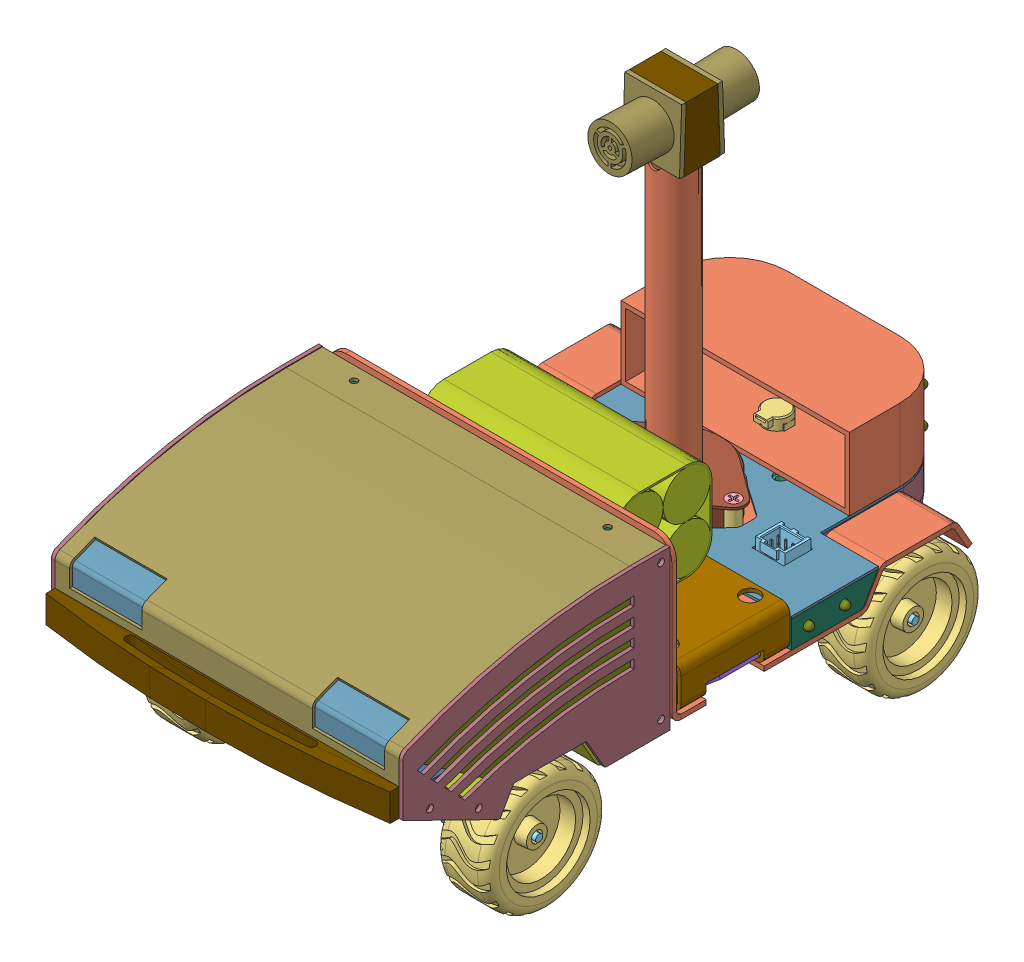
SolidWorks assembly ASSEMBLY, TEST, configuration Default. Lengths in mm.
Overall size (124.43 170.93 223.86).
89 component instances, 42 part files, 3 mates.
Components (placement in the parent):
- SCOUT, TOP LEVEL-1: SCOUT, TOP LEVEL [Default] at (-54.0107 -26.6072 26.8568) size (124.43 170.93 223.86)
  - 6655k13 Thrust Washers-1: 6655k13 Thrust Washers [Default] at (-7.8856 2.7539 2.2902) size (14.15 14.15 4.9)
  - REAR, TOP LEVEL-1: REAR, TOP LEVEL [Default] at (-50.0168 -33.3245 -47.0081) x (-1 0 0) z (0 0 -1) size (124.43 170.93 120.66)
    - PLATE, REAR-1: PLATE, REAR [Default] at (-42.1312 28.0774 12.7174) size (120.65 55.63 120.66)
    - WHEEL ASSEMBLY-1: WHEEL ASSEMBLY [Default] at (7.6153 26.9792 58.7651) x (0 0 1) z (1 0 0) size (42.46 78.6 70.03) (flexible)
      - Pololu 49x19 Wheel-1: Pololu 49x19 Wheel [Default] at (-19.8703 11.8393 2.4418) size (42.46 42.56 19)
      - Pololu Extended Micro Metal Bracket-1: Pololu Extended Micro Metal Bracket [Default] at (-19.8703 6.8393 -18.4366) size (26.6 22.49 26.04)
      - Pololu 298-1 Motor-1: Pololu 298-1 Motor [Default] at (-19.8703 11.8393 -25.1366) x (0 0 -1) z (0 1 0) size (35.87 12 10)
    - WHEEL ASSEMBLY-2: WHEEL ASSEMBLY [Default] at (-91.8778 26.9792 19.0244) x (0 0 -1) z (-1 0 0) size (42.46 78.6 70.03) (flexible)
      - Pololu 49x19 Wheel-1: Pololu 49x19 Wheel [Default] at (-19.8703 11.8393 2.4418) size (42.46 42.56 19)
      - Pololu Extended Micro Metal Bracket-1: Pololu Extended Micro Metal Bracket [Default] at (-19.8703 6.8393 -18.4366) size (26.6 22.49 26.04)
      - Pololu 298-1 Motor-1: Pololu 298-1 Motor [Default] at (-19.8703 11.8393 -25.1366) x (0 0 -1) z (0 1 0) size (35.87 12 10)
    - Socket Head Cap Screw_AI-9: Socket Head Cap Screw_AI [HX-SHCS 0.086-56x0.4375x0.4375-N] at (-77.6912 31.9128 47.8948) x (0 -1 0) z (-0.381305 0 -0.924449) size (13.3 3.56 3.56)
    - Socket Head Cap Screw_AI-10: Socket Head Cap Screw_AI [HX-SHCS 0.086-56x0.4375x0.4375-N] at (-77.6912 31.9128 29.8948) x (0 -1 0) z (0 0 1) size (13.3 3.56 3.56)
    - Socket Head Cap Screw_AI-11: Socket Head Cap Screw_AI [HX-SHCS 0.086-56x0.4375x0.4375-N] at (-6.5712 31.9128 29.8948) x (0 -1 0) z (0 0 1) size (13.3 3.56 3.56)
    - Socket Head Cap Screw_AI-12: Socket Head Cap Screw_AI [HX-SHCS 0.086-56x0.4375x0.4375-N] at (-6.5712 31.9128 47.8948) x (0 -1 0) z (0 0 1) size (13.3 3.56 3.56)
    - 4000mAh 7.4V Battery Pack-1: 4000mAh 7.4V Battery Pack [Default] at (-42.1312 61.2244 -25.3842) x (0 0 -1) z (1 0 0) size (34.29 34.29 68.58)
    - SENSOR, GP2Y0D810-1: SENSOR, GP2Y0D810 [Default] at (9.9271 36.6454 -23.9419) x (0 0 -1) z (0.766044 0.642788 0) size (28.32 10.54 8.89)
    - SENSOR, GP2Y0D810-2: SENSOR, GP2Y0D810 [Default] at (-94.1896 36.6454 -23.9419) x (0 0 -1) z (0.766044 -0.642788 0) size (28.32 10.54 8.89)
    - Battery Support-1: Battery Support [Default] at (-42.1312 29.7284 -26.0192) size (120.65 27.05 38.1)
    - Mounting Block-1: Mounting Block [Default] at (-42.1312 36.0784 -35.6712) x (-1 0 0) z (0 0 -1) size (25.4 12.7 25.4)
    - PF35T-48-1: PF35T-48 [Default] at (-42.1312 31.7284 12.5888) x (-1 0 0) z (0 0 -1) size (50 29.2 35)
    - MaxSonar EZ1-1: MaxSonar EZ1 [Default] at (-42.1312 153.1691 6.6293) x (-1 0 0) z (0 0.034899 -0.999391) size (19.94 22.1 16.38)
    - MaxSonar EZ1-2: MaxSonar EZ1 [Default] at (-42.1312 153.1691 18.5483) x (1 0 0) z (0 0.034899 0.999391) size (19.94 22.1 16.38)
    - BUMPER, REAR-1: BUMPER, REAR [Default] at (-42.1312 29.7284 53.2288) x (-1 0 0) z (0 0 -1) size (80.01 9.53 54.3)
    - PLATE, REAR COVER-1: PLATE, REAR COVER [Default] at (-42.1312 39.2534 72.2788) size (120.65 0.81 81.14)
    - MOUNTING BLOCK, COLOR SENSOR-1: MOUNTING BLOCK, COLOR SENSOR [Default] at (-97.6937 29.7284 5.6038) size (9.53 9.53 30.46)
    - MOUNTING BLOCK, COLOR SENSOR-2: MOUNTING BLOCK, COLOR SENSOR [Default] at (13.4313 29.7284 5.6038) size (9.53 9.53 30.46)
    - SENSOR, COLOR LED-1: SENSOR, COLOR LED [Default] at (-24.0807 23.782 31.9371) x (0 0 -1) z (-0.409692 -0.912224 0) size (5.83 3.66 3.66)
    - SENSOR, COLOR LED-2: SENSOR, COLOR LED [Default] at (-67.3741 22.996 31.9371) x (0 0 -1) z (-0.202984 -0.979182 0) size (5.83 3.66 3.66)
    - COPPER CONTACT-1: COPPER CONTACT [Default] at (-53.2437 34.4909 64.0238) size (15.88 6.35 4.45)
    - COPPER CONTACT-2: COPPER CONTACT [Default] at (-31.0187 34.4909 64.0238) size (15.88 6.35 4.45)
    - MOUNTING BLOCK, SONAR-1: MOUNTING BLOCK, SONAR [Default] at (-42.1312 153.0989 12.5888) x (-1 0 0) z (0 0 -1) size (19.94 22.23 12.7)
    - SHAFT, SONAR MOUNT-1: SHAFT, SONAR MOUNT [Default] at (-42.1312 52.5784 12.5888) x (-0.538443 0 0.842662) z (-0.842662 0 -0.538443) size (4.76 102.11 4.76)
    - SHAFT, SONAR SUPPORT-1: SHAFT, SONAR SUPPORT [Default] at (-42.1312 46.7284 12.5888) x (0.999987 0 0.005105) z (-0.005105 0 0.999987) size (14.22 95.57 14.22)
    - SHAFT, STEPPER SUPPORT-1: SHAFT, STEPPER SUPPORT [Default] at (-63.1312 29.6724 12.5888) size (4.76 16.26 4.76)
    - SHAFT, STEPPER SUPPORT-2: SHAFT, STEPPER SUPPORT [Default] at (-21.1312 29.6724 12.5888) x (0.987866 0 -0.155311) z (0.155311 0 0.987866) size (4.76 16.26 4.76)
    - Flat Head 100 Screw_AI-6: Flat Head 100 Screw_AI [CR-FHM1 0.112-40x0.25x0.25-N] at (-63.1312 46.7284 12.5888) x (0 -1 0) z (0 0 1) size (6.35 4.85 4.85)
    - Flat Head 100 Screw_AI-7: Flat Head 100 Screw_AI [CR-FHM1 0.112-40x0.25x0.25-N] at (-21.1312 46.7284 12.5888) x (0 -1 0) z (0 0 1) size (6.35 4.85 4.85)
    - CONNECTOR, MOLEX 6 PIN-1: CONNECTOR, MOLEX 6 PIN [Default] at (-80.2263 37.7912 12.5433) size (10.34 13.8 9.75)
    - SENSOR, COLOR LED-3: SENSOR, COLOR LED [Default] at (-64.0196 42.7147 3.5765) x (1 0 0) z (0 0.700538 -0.713616) size (5.83 3.66 3.66)
    - SENSOR, COLOR LED-4: SENSOR, COLOR LED [Default] at (-64.0196 42.7147 -9.1235) x (1 0 0) z (0 0.700538 -0.713616) size (5.83 3.66 3.66)
    - SENSOR, COLOR LED-5: SENSOR, COLOR LED [Default] at (-20.2429 42.7147 20.3311) x (-1 0 0) z (0 0.700538 0.713616) size (5.83 3.66 3.66)
    - SENSOR, COLOR LED-6: SENSOR, COLOR LED [Default] at (-20.2429 42.7147 7.6311) x (-1 0 0) z (0 0.700538 0.713616) size (5.83 3.66 3.66)
    - MOUNTING BLOCK, REAR-1: MOUNTING BLOCK, REAR [Default] at (-58.0062 34.4909 31.0038) size (9.53 9.53 28.57)
    - MOUNTING BLOCK, REAR-2: MOUNTING BLOCK, REAR [Default] at (-26.2562 34.4909 31.0038) size (9.53 9.53 28.57)
    - SW3dPS-Sliderswitch-1: SW3dPS-Sliderswitch [Standard] at (-81.1109 44.0794 -21.7288) (suppressed, hidden)
  - FRONT, TOP LEVEL-1: FRONT, TOP LEVEL [Default] at (-84.349 -51.7544 28.3431) x (-1 0 0) z (0 0 -1) size (123.38 89.85 131.19)
    - PLATE, FRONT-1: PLATE, FRONT [Default] at (-76.4634 46.5072 -32.0242) size (120.65 12.1 60.8)
    - WHEEL ASSEMBLY-1: WHEEL ASSEMBLY [Default] at (-26.7168 45.4091 2.1802) x (0 0 1) z (1 0 0) size (42.46 78.6 70.03) (flexible)
      - Pololu 49x19 Wheel-1: Pololu 49x19 Wheel [Default] at (-19.8703 11.8393 2.4418) size (42.46 42.56 19)
      - Pololu Extended Micro Metal Bracket-1: Pololu Extended Micro Metal Bracket [Default] at (-19.8703 6.8393 -18.4366) size (26.6 22.49 26.04)
      - Pololu 298-1 Motor-1: Pololu 298-1 Motor [Default] at (-19.8703 11.8393 -25.1366) x (0 0 -1) z (0 1 0) size (35.87 12 10)
    - WHEEL ASSEMBLY-2: WHEEL ASSEMBLY [Default] at (-126.21 45.4091 -37.5605) x (0 0 -1) z (-1 0 0) size (42.46 78.6 70.03) (flexible)
      - Pololu 49x19 Wheel-1: Pololu 49x19 Wheel [Default] at (-19.8703 11.8393 2.4418) size (42.46 42.56 19)
      - Pololu Extended Micro Metal Bracket-1: Pololu Extended Micro Metal Bracket [Default] at (-19.8703 6.8393 -18.4366) size (26.6 22.49 26.04)
      - Pololu 298-1 Motor-1: Pololu 298-1 Motor [Default] at (-19.8703 11.8393 -25.1366) x (0 0 -1) z (0 1 0) size (35.87 12 10)
    - Socket Head Cap Screw_AI-11: Socket Head Cap Screw_AI [HX-SHCS 0.086-56x0.4375x0.4375-N] at (-112.0234 50.3426 -8.6902) x (0 -1 0) z (0.989468 0 0.144748) size (13.3 3.56 3.56)
    - Socket Head Cap Screw_AI-12: Socket Head Cap Screw_AI [HX-SHCS 0.086-56x0.4375x0.4375-N] at (-40.9034 50.3426 -8.6902) x (0 -1 0) z (0.700957 0 0.713204) size (13.3 3.56 3.56)
    - SENSOR, GP2Y0D810-2: SENSOR, GP2Y0D810 [Default] at (-76.7491 52.0249 -21.9932) x (1 0 0) z (0 -0.642788 0.766044) size (28.32 10.54 8.89)
    - BUMPER, FRONT-1: BUMPER, FRONT [Default] at (-76.4634 36.9822 -30.9902) x (-1 0 0) z (0 0 -1) size (69.85 9.53 6.35)
    - Mounting Block-1: Mounting Block [Default] at (-76.4634 54.5082 12.4258) size (25.4 12.7 25.4)
    - Socket Head Shoulder Screw2_AI-2: Socket Head Shoulder Screw2_AI [SHSSCREW 0.25x1.5-N] at (-76.4634 54.5082 2.5706) x (0 0 1) z (-0.728467 -0.685081 0) size (52.4 9.53 9.53)
    - Socket Head Cap Screw_AI-13: Socket Head Cap Screw_AI [HX-SHCS 0.086-56x0.4375x0.4375-N] at (-40.9034 51.2773 -26.6902) x (0 -1 0) z (-0.957829 0 -0.287339) size (13.3 3.56 3.56)
    - Socket Head Cap Screw_AI-14: Socket Head Cap Screw_AI [HX-SHCS 0.086-56x0.4375x0.4375-N] at (-112.0234 51.2773 -26.6902) x (0 -1 0) z (-0.957829 0 -0.287339) size (13.3 3.56 3.56)
    - PCB, MAIN-1: PCB, MAIN [Default] at (-76.4634 67.2082 -21.6044) size (114.3 1.6 88.9)
    - PLATE, FRONT BUMPER-1: PLATE, FRONT BUMPER [Default] at (-76.4634 48.9202 -22.7941) size (120.65 17.91 44.79)
    - COVER, FRONT-1: COVER, FRONT [Default] at (-76.4634 65.9445 25.1258) size (120.65 35.94 93.73)
    - PLATE, FRONT SIDE-1: PLATE, FRONT SIDE [Default] at (-16.1384 46.5072 25.1258) x (0 0 -1) z (1 0 0) size (93.73 55.63 1.27)
    - SW3dPS-USB_mini_B-1: SW3dPS-USB_mini_B [По умолчанию] at (-54.9865 68.8084 -58.5669) x (-1 0 0) z (0 0 -1) (suppressed, hidden)
    - HEADLIGHT COVER, FRONT-1: HEADLIGHT COVER, FRONT [Default] at (-103.1334 74.8345 -67.5842) x (-1 0 0) z (0 0 -1) size (31.75 14.4 11.68)
    - HEADLIGHT COVER, FRONT-2: HEADLIGHT COVER, FRONT [Default] at (-18.0434 74.8345 -67.5842) x (-1 0 0) z (0 0 -1) size (31.75 14.4 11.68)
    - PLATE, FRONT SIDE-2: PLATE, FRONT SIDE [Default] at (-138.0584 46.5072 25.1258) x (0 0 -1) z (1 0 0) size (93.73 55.63 1.27)
    - STRUT, FRONT SIDE-1: STRUT, FRONT SIDE [Default] at (-76.4634 98.9582 21.9508) size (120.65 3.17 6.35)
    - FILTER, FRONT COVER-1: FILTER, FRONT COVER [Default] at (-19.1356 62.8553 14.5951) x (0 0 -1) z (1 0 0) size (76.17 31.33 3)
    - FILTER, FRONT COVER-2: FILTER, FRONT COVER [Default] at (-136.7884 62.8559 13.2551) x (0 0 -1) z (1 0 0) size (76.17 31.33 3)
    - Orb LED-1: Orb LED [Default] at (-118.9744 68.8084 -63.3886) size (6.35 9.53 6.35)
    - Orb LED-2: Orb LED [Default] at (-34.5831 68.8084 -63.3886) size (6.35 9.53 6.35)
    - BUMPER, FRONT SWITCHED-1: BUMPER, FRONT SWITCHED [Default] at (-76.4634 70.707 -70.1877) x (-1 0 0) z (0 0 -1) size (120.65 9.53 7.62)
  - BUMPER, FRONT SWITCHED-1: BUMPER, FRONT SWITCHED [Default] at (-7.8856 18.9527 98.5308) size (120.65 9.53 7.62)
- Test Assembly-1: Test Assembly [Default] at (-141.4296 -33.6993 -27.6073) x (-1 0 0) z (0 0 -1) size (80.01 25.4 38.1)
  - REAR ACCESSORY-1: REAR ACCESSORY [Default] at (-79.5333 13.0209 64.8228) size (120.65 126.74 88.28) (hidden)
  - gp2d12-1: gp2d12 [Default] at (-79.1744 21.9212 49.7353) x (-1 0 0) z (0 0 1) size (44.5 18.9 13.5)
  - VEHICLE, BASEPLATE-1: VEHICLE, BASEPLATE [Default] at (-79.5333 13.8337 64.8228) size (80.01 25.4 38.1)
  - SMD Buzzer-1: SMD Buzzer [Default] at (-79.4357 15.4212 41.3375) size (9.15 4 10.15)
  - SENSOR, COLOR LED-1: SENSOR, COLOR LED [Default] at (-99.544 32.8837 21.5956) x (0 0 -1) z (1 0 0) size (5.83 3.66 3.66)
  - SENSOR, COLOR LED-2: SENSOR, COLOR LED [Default] at (-99.544 20.1837 21.5956) x (0 0 -1) z (1 0 0) size (5.83 3.66 3.66)
  - SENSOR, COLOR LED-3: SENSOR, COLOR LED [Default] at (-36.044 32.8837 21.5956) x (0 0 -1) z (1 0 0) size (5.83 3.66 3.66)
  - SENSOR, COLOR LED-4: SENSOR, COLOR LED [Default] at (-36.044 20.1837 21.5956) x (0 0 -1) z (1 0 0) size (5.83 3.66 3.66)
Mates (geometry in assembly coordinates):
- Coincident1: coincident aligned: plane of SCOUT, TOP LEVEL-1/REAR, TOP LEVEL-1/BUMPER, REAR-1 through (-101.9013 -20.6784 -73.3801) normal (-1 0 0); plane of Test Assembly-1/VEHICLE, BASEPLATE-1 through (-101.9013 5.5344 -54.3301) normal (-1 0 0)
- Coincident2: coincident anti-aligned: plane of SCOUT, TOP LEVEL-1/REAR, TOP LEVEL-1/PLATE, REAR COVER-1 through (-42.1722 -19.8656 -72.1213) normal (0 1 0); plane of Test Assembly-1/VEHICLE, BASEPLATE-1 through (-42.2113 -19.8656 -72.1101) normal (0 -1 0)
- Coincident3: coincident aligned: plane of SCOUT, TOP LEVEL-1/REAR, TOP LEVEL-1/BUMPER, REAR-1 through (-80.9463 -20.6784 -92.4301) normal (0 0 -1); plane of Test Assembly-1/VEHICLE, BASEPLATE-1 through (-42.2113 5.5344 -92.4301) normal (0 0 -1)
